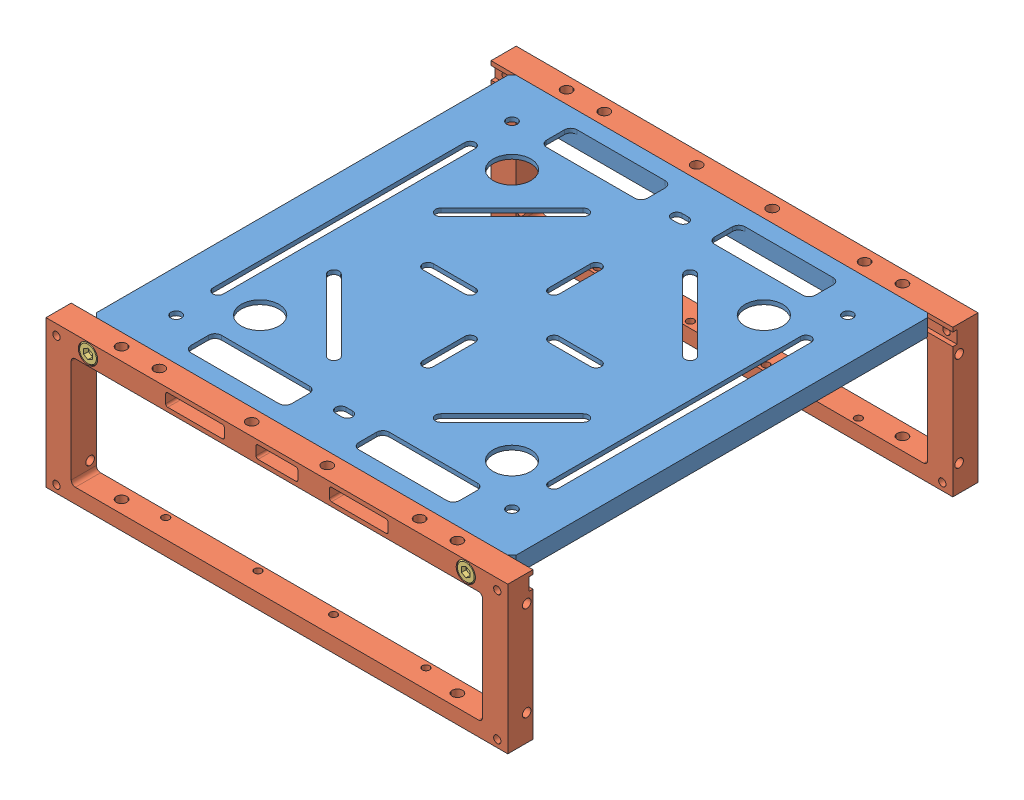
SolidWorks assembly expansion bay, configuration Default. Lengths in mm.
Overall size (110 35 112).
7 component instances, 3 part files, 7 mates.
Components (placement in the parent):
- expansion bay base-1: expansion bay base [Default] at (-16.5029 50.9616 130.8906) size (100 4 102)
- expansion bracket-1: expansion bracket [Default] at (-21.5029 54.9616 136.8906) x (1 0 0) z (0 1 0) size (110 6 35)
- socket head cap screw_am-2: socket head cap screw_am [B18.3.1M - 2.5 x 0.45 x 5 Hex SHCS -- 5NHX] at (78.4971 52.4616 136.8906) x (0 0 -1) z (1 0 0) size (7.5 4.5 4.5)
- socket head cap screw_am-3: socket head cap screw_am [B18.3.1M - 2.5 x 0.45 x 5 Hex SHCS -- 5NHX] at (-11.5029 52.4616 136.8906) x (0 0 -1) z (1 0 0) size (7.5 4.5 4.5)
- socket head cap screw_am-4: socket head cap screw_am [B18.3.1M - 2.5 x 0.45 x 5 Hex SHCS -- 5NHX] at (-11.5029 52.4616 24.8906) x (0 0 1) z (-1 0 0) size (7.5 4.5 4.5)
- expansion bracket-3: expansion bracket [Default] at (88.4971 54.9616 24.8906) x (-1 0 0) z (0 1 0) size (110 6 35)
- socket head cap screw_am-5: socket head cap screw_am [B18.3.1M - 2.5 x 0.45 x 5 Hex SHCS -- 5NHX] at (78.4971 52.4616 24.8906) x (0 0 1) z (-1 0 0) size (7.5 4.5 4.5)
Mates (geometry in assembly coordinates):
- Coincident1: coincident anti-aligned: plane of expansion bay base-1 through (-16.5029 50.9616 131.8906) normal (0 0 1); plane of expansion bracket-1 through (-21.5029 54.9616 131.8906) normal (0 0 -1)
- Coincident2: coincident anti-aligned: plane of expansion bay base-1 through (-16.5029 53.9616 131.8906) normal (0 1 0); plane of expansion bracket-1 through (-21.5029 53.9616 131.8906) normal (0 -1 0)
- Concentric1: concentric aligned: cylinder of expansion bay base-1 through (78.4971 52.4616 131.8906) axis (0 0 1) radius 1.25; cylinder of expansion bracket-1 through (78.4971 52.4616 136.8906) axis (0 0 1) radius 1.45
- Concentric2: concentric aligned: cylinder of expansion bracket-1 through (78.4971 52.4616 136.8906) axis (0 0 1) radius 1.45; cylinder of socket head cap screw_am-2 through (78.4971 52.4616 168.6406) axis (0 0 1) radius 2.25
- Coincident3: coincident anti-aligned: plane of expansion bracket-1 through (79.9471 52.4616 134.3906) normal (0 0 1); plane of socket head cap screw_am-2 through (78.4971 54.7116 134.3906) normal (0 0 -1)
- Concentric3: concentric aligned: cylinder of expansion bracket-1 through (-11.5029 52.4616 136.8906) axis (0 0 1) radius 1.45; cylinder of socket head cap screw_am-3 through (-11.5029 52.4616 168.6406) axis (0 0 1) radius 2.25
- Coincident4: coincident anti-aligned: plane of expansion bracket-1 through (-10.0529 52.4616 134.3906) normal (0 0 1); plane of socket head cap screw_am-3 through (-11.5029 54.7116 134.3906) normal (0 0 -1)
